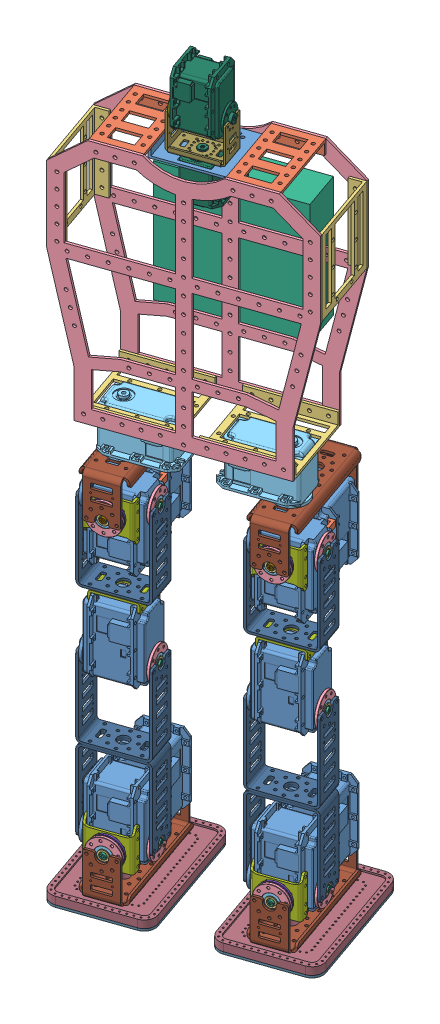
SolidWorks assembly main_new_feet_no_arm_update_motor, configuration Default. Lengths in mm.
Overall size (261.31 695.74 185.95).
113 component instances, 25 part files, 43 mates.
Components (placement in the parent):
- leg_l2-1: leg_l2 [Default] at (32.8984 -224.9307 -176.674) x (0.329122 0 0.944287) z (-0.944287 0 0.329122) size (106.88 70.06 58.88)
  - MX-106T_step-1: MX-106T_step [Default] at origin size (40.2 65.92 55.3)
  - MX-106T_step-2: MX-106T_step [Default] at (-44 0 0) x (0 0 1) z (-1 0 0) size (40.2 65.92 55.3)
  - FR08-X101_2017-1: FR08-X101_2017 [Default] at (-27 -7 -17) x (0 -1 0) z (0 0 1) size (28 12.3 4.8)
  - FR08-X101_2017-2: FR08-X101_2017 [Default] at (-27 -7 17) x (0 1 0) z (0 0 -1) size (28 12.3 4.8)
  - RX64-CAP_2017-1: RX64-CAP_2017 [Default] at (0 0 -25.78) x (0.56381 0.825904 0) z (0 0 -1) size (9.5 9.5 2.2)
  - HN05-I101_2017-1: HN05-I101_2017 [Default] at (0 0 -26.02) x (0.824833 -0.565376 0) z (0.565376 0.824833 0) size (28 3.77 28)
  - MF128ZZ_2017-1: MF128ZZ_2017 [Default] at (0 0 -22.3) x (-0.923728 -0.383049 0) z (0.383049 -0.923728 0) size (14 3.48 14)
  - WB_M2.5X8_2017-1: WB_M2.5X8_2017 [Default] at (0 0 -28.08) x (0 0 1) z (0.825904 -0.56381 0) size (5.5 4.5 4.5)
  - FR05-S101_2017-1: FR05-S101_2017 [Default] at (24 0 0) x (0 1 0) z (0 0 1) size (36 9.31 38.02)
  - FR05-F101_2017-1: FR05-F101_2017 [Default] at (24 0 0) x (0 -0.707107 0.707107) z (1 0 0) size (27 27 5)
  - MF128ZZ_2017-2: MF128ZZ_2017 [Default] at (26.3 0 0) x (0 -1 0) z (0 0 1) size (14 3.48 14)
  - WB_M2.5X8_step-1: WB_M2.5X8_step [Default] at (32.08 0 0) x (-1 0 0) z (0 0.546944 0.837169) size (10.5 4.5 4.5)
  - HN05-I101_2017-2: HN05-I101_2017 [Default] at (30.02 0 0) x (0 -1 0) z (0 0 1) size (28 3.77 28)
  - RX64-CAP_2017-2: RX64-CAP_2017 [Default] at (29.78 0 0) x (0 0.837169 -0.546944) z (1 0 0) size (9.5 9.5 2.2)
- leg_l3-2: leg_l3 [Default] at (28.5454 -310.8375 -119.8421) x (0.944287 0 -0.329122) z (0 1 0) size (58.88 41.6 149.21)
  - HW-64106HXL_2017-1: HW-64106HXL_2017 [Default] at (-3.1848 38.233 13.9067) size (56 28 75)
  - FR05-S101_2017-1: FR05-S101_2017 [Default] at (22.8152 52.233 13.9067) x (0 -1 0) z (1 0 0) size (36 9.31 38.02)
  - MX-106T_step-1: MX-106T_step [Default] at (22.8152 52.233 -40.5933) x (0 1 0) z (-1 0 0) size (40.2 65.92 55.3)
  - HN05-I101_2017-1: HN05-I101_2017 [Default] at (48.8352 52.233 -40.5933) x (0 -0.637924 -0.7701) z (0 -0.7701 0.637924) size (28 3.77 28)
  - RX64-CAP_2017-1: RX64-CAP_2017 [Default] at (48.5952 52.233 -40.5933) x (0 0.837169 -0.546944) z (1 0 0) size (9.5 9.5 2.2)
  - MF128ZZ_2017-1: MF128ZZ_2017 [Default] at (45.1152 52.233 -40.5933) x (0 -0.162836 -0.986653) z (0 -0.986653 0.162836) size (14 3.48 14)
  - WB_M2.5X8_2017-1: WB_M2.5X8_2017 [Default] at (50.8952 52.233 -40.5933) x (-1 0 0) z (0 0.546944 0.837169) size (5.5 4.5 4.5)
- leg_l4-1: leg_l4 [Default] at (8.2175 -492.0992 -119.3689) x (0.944287 0 -0.329122) z (0 1 0) size (56 28 150)
  - HW-64106HXL_2017-1: HW-64106HXL_2017 [Default] at (16.1663 31.9894 68.6685) size (56 28 75)
  - HW-64106HXL_2017-2: HW-64106HXL_2017 [Default] at (68.1663 31.9894 68.6685) x (-1 0 0) z (0 0 -1) size (56 28 75)
- leg_l5-1: leg_l5 [Default] at (63.8478 -442.1127 -223.3318) x (0.89528 -0.033567 0.444237) z (-0.424558 -0.366444 0.827931) size (104.02 99.97 119.36)
  - MX-106T_step-1: MX-106T_step [Default] at (-5.1915 -29.4269 71.3073) x (-0.714144 -0.278818 -0.642073) z (-0.699193 0.240141 0.673395) size (40.2 65.92 55.3)
  - MX-106T_step-2: MX-106T_step [Default] at (-36.6138 -41.6949 43.056) x (0.699193 -0.240141 -0.673395) z (-0.714144 -0.278818 -0.642073) size (40.2 65.92 55.3)
  - FR08-X101_2017-1: FR08-X101_2017 [Default] at (-36.5946 -26.3638 62.8539) x (-0.033567 0.929835 -0.366444) z (0.699193 -0.240141 -0.673395) size (28 12.3 4.8)
  - FR08-X101_2017-2: FR08-X101_2017 [Default] at (-12.8221 -34.5286 39.9585) x (0.033567 -0.929835 0.366444) z (-0.699193 0.240141 0.673395) size (28 12.3 4.8)
  - HN05-I101_2017-1: HN05-I101_2017 [Default] at (13.0015 -35.6754 53.7855) x (0.048348 -0.923861 0.379661) z (0.713296 0.298014 0.634347) size (28 3.77 28)
  - RX64-CAP_2017-1: RX64-CAP_2017 [Default] at (12.8337 -35.6178 53.9472) x (-0.430608 0.610431 -0.664793) z (0.699193 -0.240141 -0.673395) size (9.5 9.5 2.2)
  - HN05-I101_2017-2: HN05-I101_2017 [Default] at (16.2471 -21.0568 90.5823) x (0.601193 -0.714144 -0.35856) z (-0.35856 -0.642073 0.677626) size (28 3.77 28)
  - RX64-CAP_2017-2: RX64-CAP_2017 [Default] at (16.0757 -21.1237 90.4282) x (-0.307188 0.949038 -0.070448) z (0.714144 0.278818 0.642073) size (9.5 9.5 2.2)
  - MF128ZZ_2017-1: MF128ZZ_2017 [Default] at (10.4005 -34.7821 56.2906) x (0.048348 -0.923861 0.379661) z (0.713296 0.298014 0.634347) size (14 3.48 14)
  - WB_M2.5X8_2017-1: WB_M2.5X8_2017 [Default] at (14.4419 -36.1701 52.3983) x (-0.699193 0.240141 0.673395) z (0.570706 0.754788 0.323403) size (5.5 4.5 4.5)
  - MF128ZZ_2017-2: MF128ZZ_2017 [Default] at (13.5905 -22.094 88.1938) x (0.601193 -0.714144 -0.35856) z (-0.35856 -0.642073 0.677626) size (14 3.48 14)
  - WB_M2.5X8_2017-2: WB_M2.5X8_2017 [Default] at (17.7183 -20.4824 91.905) x (-0.714144 -0.278818 -0.642073) z (-0.628994 -0.146927 0.763399) size (5.5 4.5 4.5)
  - FR05-S101_2017-1: FR05-S101_2017 [Default] at (11.948 -22.7353 86.717) x (0.033567 -0.929835 0.366444) z (0.699193 -0.240141 -0.673395) size (36 9.31 38.02)
  - FR05-F101_2017-1: FR05-F101_2017 [Default] at (11.948 -22.7353 86.717) x (0.699193 -0.240141 -0.673395) z (0.714144 0.278818 0.642073) size (27 27 5)
- HW-64106HXW_2017-3: HW-64106HXW_2017 [Default] at (141.3019 -187.9307 -286.4689) x (0.329122 0 0.944287) z (0 -1 0) size (105 37.08 40)
- leg_l2-2: leg_l2 [Default] at (148.5736 -224.9307 -216.9914) x (0.329122 0 0.944287) z (-0.944287 0 0.329122) size (106.88 70.06 58.88)
  - MX-106T_step-1: MX-106T_step [Default] at origin size (40.2 65.92 55.3)
  - MX-106T_step-2: MX-106T_step [Default] at (-44 0 0) x (0 0 1) z (-1 0 0) size (40.2 65.92 55.3)
  - FR08-X101_2017-1: FR08-X101_2017 [Default] at (-27 -7 -17) x (0 -1 0) z (0 0 1) size (28 12.3 4.8)
  - FR08-X101_2017-2: FR08-X101_2017 [Default] at (-27 -7 17) x (0 1 0) z (0 0 -1) size (28 12.3 4.8)
  - RX64-CAP_2017-1: RX64-CAP_2017 [Default] at (0 0 -25.78) x (0.56381 0.825904 0) z (0 0 -1) size (9.5 9.5 2.2)
  - HN05-I101_2017-1: HN05-I101_2017 [Default] at (0 0 -26.02) x (0.824833 -0.565376 0) z (0.565376 0.824833 0) size (28 3.77 28)
  - MF128ZZ_2017-1: MF128ZZ_2017 [Default] at (0 0 -22.3) x (-0.923728 -0.383049 0) z (0.383049 -0.923728 0) size (14 3.48 14)
  - WB_M2.5X8_2017-1: WB_M2.5X8_2017 [Default] at (0 0 -28.08) x (0 0 1) z (0.825904 -0.56381 0) size (5.5 4.5 4.5)
  - FR05-S101_2017-1: FR05-S101_2017 [Default] at (24 0 0) x (0 1 0) z (0 0 1) size (36 9.31 38.02)
  - FR05-F101_2017-1: FR05-F101_2017 [Default] at (24 0 0) x (0 -0.707107 0.707107) z (1 0 0) size (27 27 5)
  - MF128ZZ_2017-2: MF128ZZ_2017 [Default] at (26.3 0 0) x (0 -1 0) z (0 0 1) size (14 3.48 14)
  - WB_M2.5X8_step-1: WB_M2.5X8_step [Default] at (32.08 0 0) x (-1 0 0) z (0 0.546944 0.837169) size (10.5 4.5 4.5)
  - HN05-I101_2017-2: HN05-I101_2017 [Default] at (30.02 0 0) x (0 -1 0) z (0 0 1) size (28 3.77 28)
  - RX64-CAP_2017-2: RX64-CAP_2017 [Default] at (29.78 0 0) x (0 0.837169 -0.546944) z (1 0 0) size (9.5 9.5 2.2)
- leg_l3-3: leg_l3 [Default] at (144.2206 -310.8375 -160.1595) x (0.944287 0 -0.329122) z (0 1 0) size (58.88 41.6 149.21)
  - HW-64106HXL_2017-1: HW-64106HXL_2017 [Default] at (-3.1848 38.233 13.9067) size (56 28 75)
  - FR05-S101_2017-1: FR05-S101_2017 [Default] at (22.8152 52.233 13.9067) x (0 -1 0) z (1 0 0) size (36 9.31 38.02)
  - MX-106T_step-1: MX-106T_step [Default] at (22.8152 52.233 -40.5933) x (0 1 0) z (-1 0 0) size (40.2 65.92 55.3)
  - HN05-I101_2017-1: HN05-I101_2017 [Default] at (48.8352 52.233 -40.5933) x (0 -0.637924 -0.7701) z (0 -0.7701 0.637924) size (28 3.77 28)
  - RX64-CAP_2017-1: RX64-CAP_2017 [Default] at (48.5952 52.233 -40.5933) x (0 0.837169 -0.546944) z (1 0 0) size (9.5 9.5 2.2)
  - MF128ZZ_2017-1: MF128ZZ_2017 [Default] at (45.1152 52.233 -40.5933) x (0 -0.162836 -0.986653) z (0 -0.986653 0.162836) size (14 3.48 14)
  - WB_M2.5X8_2017-1: WB_M2.5X8_2017 [Default] at (50.8952 52.233 -40.5933) x (-1 0 0) z (0 0.546944 0.837169) size (5.5 4.5 4.5)
- leg_l4-2: leg_l4 [Default] at (123.8927 -492.0992 -159.6864) x (0.944287 0 -0.329122) z (0 1 0) size (56 28 150)
  - HW-64106HXL_2017-1: HW-64106HXL_2017 [Default] at (16.1663 31.9894 68.6685) size (56 28 75)
  - HW-64106HXL_2017-2: HW-64106HXL_2017 [Default] at (68.1663 31.9894 68.6685) x (-1 0 0) z (0 0 -1) size (56 28 75)
- leg_l5-2: leg_l5 [Default] at (179.523 -442.1127 -263.6493) x (0.89528 -0.033567 0.444237) z (-0.424558 -0.366444 0.827931) size (104.02 99.97 119.36)
  - MX-106T_step-1: MX-106T_step [Default] at (-5.1915 -29.4269 71.3073) x (-0.714144 -0.278818 -0.642073) z (-0.699193 0.240141 0.673395) size (40.2 65.92 55.3)
  - MX-106T_step-2: MX-106T_step [Default] at (-36.6138 -41.6949 43.056) x (0.699193 -0.240141 -0.673395) z (-0.714144 -0.278818 -0.642073) size (40.2 65.92 55.3)
  - FR08-X101_2017-1: FR08-X101_2017 [Default] at (-36.5946 -26.3638 62.8539) x (-0.033567 0.929835 -0.366444) z (0.699193 -0.240141 -0.673395) size (28 12.3 4.8)
  - FR08-X101_2017-2: FR08-X101_2017 [Default] at (-12.8221 -34.5286 39.9585) x (0.033567 -0.929835 0.366444) z (-0.699193 0.240141 0.673395) size (28 12.3 4.8)
  - HN05-I101_2017-1: HN05-I101_2017 [Default] at (13.0015 -35.6754 53.7855) x (0.048348 -0.923861 0.379661) z (0.713296 0.298014 0.634347) size (28 3.77 28)
  - RX64-CAP_2017-1: RX64-CAP_2017 [Default] at (12.8337 -35.6178 53.9472) x (-0.430608 0.610431 -0.664793) z (0.699193 -0.240141 -0.673395) size (9.5 9.5 2.2)
  - HN05-I101_2017-2: HN05-I101_2017 [Default] at (16.2471 -21.0568 90.5823) x (0.601193 -0.714144 -0.35856) z (-0.35856 -0.642073 0.677626) size (28 3.77 28)
  - RX64-CAP_2017-2: RX64-CAP_2017 [Default] at (16.0757 -21.1237 90.4282) x (-0.307188 0.949038 -0.070448) z (0.714144 0.278818 0.642073) size (9.5 9.5 2.2)
  - MF128ZZ_2017-1: MF128ZZ_2017 [Default] at (10.4005 -34.7821 56.2906) x (0.048348 -0.923861 0.379661) z (0.713296 0.298014 0.634347) size (14 3.48 14)
  - WB_M2.5X8_2017-1: WB_M2.5X8_2017 [Default] at (14.4419 -36.1701 52.3983) x (-0.699193 0.240141 0.673395) z (0.570706 0.754788 0.323403) size (5.5 4.5 4.5)
  - MF128ZZ_2017-2: MF128ZZ_2017 [Default] at (13.5905 -22.094 88.1938) x (0.601193 -0.714144 -0.35856) z (-0.35856 -0.642073 0.677626) size (14 3.48 14)
  - WB_M2.5X8_2017-2: WB_M2.5X8_2017 [Default] at (17.7183 -20.4824 91.905) x (-0.714144 -0.278818 -0.642073) z (-0.628994 -0.146927 0.763399) size (5.5 4.5 4.5)
  - FR05-S101_2017-1: FR05-S101_2017 [Default] at (11.948 -22.7353 86.717) x (0.033567 -0.929835 0.366444) z (0.699193 -0.240141 -0.673395) size (36 9.31 38.02)
  - FR05-F101_2017-1: FR05-F101_2017 [Default] at (11.948 -22.7353 86.717) x (0.699193 -0.240141 -0.673395) z (0.714144 0.278818 0.642073) size (27 27 5)
- HW-64106HXW_2017-5: HW-64106HXW_2017 [Default] at (25.6267 -187.9307 -246.1515) x (0.329122 0 0.944287) z (0 -1 0) size (105 37.08 40)
- FR07-H101K-1: FR07-H101K [Default] at (93.0399 76.5333 -190.2227) x (-0.944287 0 0.329122) z (0 1 0) size (44 26 32.5)
- leg_l6_new_feet-1: leg_l6_new_feet [Default] at (87.7926 -593.8701 -169.2992) x (-0.329122 0 -0.944287) z (0 1 0) size (120 80 47.5)
  - HW-64106HXW_2017-1: HW-64106HXW_2017 [Default] at (-3.9692 33.4087 61.4394) size (105 37.08 40)
  - foot_new-1: foot_new [Default] at (44.5308 49.4087 55.9394) x (1 0 0) z (0 -1 0) size (120 7 80)
  - Part4^leg_l6_new_feet-1: Part4^leg_l6_new_feet [Default] at (44.5308 49.4087 55.9394) x (-1 0 0) z (0 0 -1) size (120 80 2) (virtual)
- leg_l6_new_feet-2: leg_l6_new_feet [Default] at (203.4678 -593.8701 -209.6167) x (-0.329122 0 -0.944287) z (0 1 0) size (120 80 47.5)
  - HW-64106HXW_2017-1: HW-64106HXW_2017 [Default] at (-3.9692 33.4087 61.4394) size (105 37.08 40)
  - foot_new-1: foot_new [Default] at (44.5308 49.4087 55.9394) x (1 0 0) z (0 -1 0) size (120 7 80)
  - Part4^leg_l6_new_feet-1: Part4^leg_l6_new_feet [Default] at (44.5308 49.4087 55.9394) x (-1 0 0) z (0 0 -1) size (120 80 2) (virtual)
- head_2_no_camera-1: head_2_no_camera [Default] at (57.4956 210.3096 -243.8587) x (0.944287 0 -0.329122) z (0.329122 0 0.944287) size (44.45 51.16 35.6)
  - MX28_step-1: MX28_step [Default] at (-26.9298 -63.9825 50.4384) x (0 0 1) z (1 0 0) size (35.6 50.71 42.6)
  - MX28_HN07-i101-1: MX28_HN07-i101 [Default] at (-4.5387 -101.2764 62.3462) x (0 0.153917 -0.988084) z (0 0.988084 0.153917) size (22 3.05 22)
  - MF106ZZ-1: MF106ZZ [Défaut] at (-4.3887 -101.2764 62.3462) x (0 0.577041 0.816715) z (0 0.816715 -0.577041) size (11.2 3 11.2)
  - RX28-CAP-1: RX28-CAP [Défaut] at (-4.3887 -101.2764 62.3462) x (0 1 0) z (-1 0 0) size (7.2 7.2 1.8)
- torso_no_arm_motor-1: torso_no_arm_motor [Default] at (90.5715 74.6103 -197.3049) x (0.944287 0 -0.329122) z (0.329122 0 0.944287) size (200 273.5 112.95)
  - torso_frame_head-1: torso_frame_head [Default] at (0 -3.827 -35) size (76 8 58.5)
  - torso_frame_link-1: torso_frame_link [Default] at (-50 -6.241 0) x (0 0 1) z (-1 0 0) size (75.11 12.7 53.47)
  - torso_frame_motor-1: torso_frame_motor [Default] at (-98.857 -88.541 0) x (0 0 1) z (-1 0 0) size (68 70 36.25)
  - torso_main-1: torso_main [Default] at (0 0 34) size (200 228.5 2.29)
  - torso_main-2: torso_main [Default] at (0 0 -36.286) size (200 228.5 2.29)
  - torso_frame_link-2: torso_frame_link [Default] at (50 -6.241 0) x (0 0 1) z (-1 0 0) size (75.11 12.7 53.47)
  - torso_frame_motor-2: torso_frame_motor [Default] at (98.857 -88.541 0) x (0 0 -1) z (1 0 0) size (68 70 36.25)
  - torso_frame_motor-3: torso_frame_motor [Default] at (10 -220.898 0) x (0 0 -1) z (0 -1 0) size (68 70 36.25)
  - torso_frame_motor-4: torso_frame_motor [Default] at (-10 -220.898 0) x (0 0 1) z (0 -1 0) size (68 70 36.25)
  - MX-64T_step-3: MX-64T_step [Default] at (61.25 -239.041 0) x (0 0 -1) z (0 -1 0) size (40.2 62.1 50)
  - MX-64T_step-4: MX-64T_step [Default] at (-61.25 -239.041 0) x (0 0 1) z (0 -1 0) size (40.2 62.1 50)
  - MX28_step-1: MX28_step [Default] at (11.9078 -61.4181 -29.7938) x (-1 0 0) z (0 1 0) size (35.6 50.71 42.6)
  - nuc-1: nuc [Default] at (0 -108.0269 -54.066) size (114.3 111.76 35.56)
- Part1^main_new_feet_no_arm_update_motor-1: Part1^main_new_feet_no_arm_update_motor [Default] at origin (virtual)
Mates (geometry in assembly coordinates):
- Concentric3: concentric anti-aligned: cylinder of leg_l2-1/HN05-I101_2017-1 through (57.4688 -224.9307 -185.2377) axis (-0.944287 0 0.329122) radius 14; cylinder of leg_l3-2/HW-64106HXL_2017-1 through (59.3385 -224.9307 -185.8894) axis (0.944287 0 -0.329122) radius 5.1
- Concentric4: concentric anti-aligned: cylinder of leg_l3-2/HN05-I101_2017-1 through (57.4688 -351.4307 -185.2377) axis (-0.944287 0 0.329122) radius 14; cylinder of leg_l4-1/HW-64106HXL_2017-1 through (59.3385 -351.4307 -185.8894) axis (0.944287 0 -0.329122) radius 5.1
- Concentric5: concentric anti-aligned: cylinder of leg_l4-1/HW-64106HXL_2017-2 through (6.4584 -495.4307 -167.4586) axis (-0.944287 0 0.329122) radius 5.1; cylinder of leg_l5-1/MX-106T_step-1 through (3.4461 -495.4307 -166.4087) axis (0.944287 0 -0.329122) radius 5
- Coincident5: coincident anti-aligned: plane of leg_l4-1/HW-64106HXL_2017-2 through (8.347 -495.4307 -168.1168) normal (0.944287 0 -0.329122); plane of leg_l5-1/MX-106T_step-1 through (8.347 -495.4307 -168.1168) normal (-0.944287 0 0.329122)
- Coincident6: coincident anti-aligned: plane of leg_l2-1/MX-106T_step-1 through (8.347 -224.9307 -168.1168) normal (-0.944287 0 0.329122); plane of leg_l3-2/HW-64106HXL_2017-1 through (8.347 -224.9307 -168.1168) normal (0.944287 0 -0.329122)
- Coincident7: coincident anti-aligned: plane of leg_l2-1/MX-106T_step-1 through (8.347 -224.9307 -168.1168) normal (-0.944287 0 0.329122); plane of leg_l3-2/HW-64106HXL_2017-1 through (8.347 -224.9307 -168.1168) normal (0.944287 0 -0.329122)
- Coincident8: coincident anti-aligned: plane of leg_l3-2/MX-106T_step-1 through (8.347 -351.4307 -168.1168) normal (-0.944287 0 0.329122); plane of leg_l4-1/HW-64106HXL_2017-1 through (8.347 -351.4307 -168.1168) normal (0.944287 0 -0.329122)
- Concentric8: concentric aligned: cylinder of HW-64106HXW_2017-3 through (159.4347 -224.9307 -185.83) axis (0.329122 0 0.944287) radius 5.1; cylinder of leg_l2-2/MX-106T_step-2 through (123.8269 -224.9307 -287.9924) axis (0.329122 0 0.944287) radius 5
- Coincident11: coincident anti-aligned: plane of HW-64106HXW_2017-3 through (125.5351 -210.0147 -283.0916) normal (0.329122 0 0.944287); plane of leg_l2-2/MX-106T_step-2 through (125.5351 -224.9307 -283.0916) normal (-0.329122 0 -0.944287)
- Concentric9: concentric aligned: cylinder of leg_l2-2/MX-106T_step-1 through (119.1213 -224.9307 -206.7261) axis (0.944287 0 -0.329122) radius 5; cylinder of leg_l3-3/HW-64106HXL_2017-1 through (124.0222 -224.9307 -208.4343) axis (0.944287 0 -0.329122) radius 5.1
- Coincident12: coincident anti-aligned: plane of leg_l2-2/MX-106T_step-1 through (124.0222 -224.9307 -208.4343) normal (-0.944287 0 0.329122); plane of leg_l3-3/HW-64106HXL_2017-1 through (124.0222 -224.9307 -208.4343) normal (0.944287 0 -0.329122)
- Concentric10: concentric aligned: cylinder of leg_l3-3/MX-106T_step-1 through (119.1213 -351.4307 -206.7261) axis (0.944287 0 -0.329122) radius 5; cylinder of leg_l4-2/HW-64106HXL_2017-1 through (124.0222 -351.4307 -208.4343) axis (0.944287 0 -0.329122) radius 5.1
- Coincident13: coincident anti-aligned: plane of leg_l3-3/MX-106T_step-1 through (124.0222 -351.4307 -208.4343) normal (-0.944287 0 0.329122); plane of leg_l4-2/HW-64106HXL_2017-1 through (124.0222 -351.4307 -208.4343) normal (0.944287 0 -0.329122)
- Concentric13: concentric anti-aligned: cylinder of leg_l4-2/HW-64106HXL_2017-2 through (122.1336 -495.4307 -207.776) axis (-0.944287 0 0.329122) radius 5.1; cylinder of leg_l5-2/MX-106T_step-1 through (119.1213 -495.4307 -206.7261) axis (0.944287 0 -0.329122) radius 5
- Coincident16: coincident anti-aligned: plane of leg_l4-2/HW-64106HXL_2017-2 through (124.0222 -495.4307 -208.4343) normal (0.944287 0 -0.329122); plane of leg_l5-2/MX-106T_step-1 through (124.0222 -495.4307 -208.4343) normal (-0.944287 0 0.329122)
- Parallel3: parallel anti-aligned: plane of leg_l2-1/MX-106T_step-1 through (32.8984 -224.9307 -176.674) normal (0.329122 0 0.944287); plane of leg_l3-2/HW-64106HXL_2017-1 through (12.9547 -296.9307 -154.8968) normal (-0.329122 0 -0.944287)
- Parallel4: parallel aligned: plane of leg_l3-2/MX-106T_step-1 through (32.8984 -351.4307 -176.674) normal (-0.329122 0 -0.944287); plane of leg_l4-1/HW-64106HXL_2017-1 through (12.9547 -423.4307 -154.8968) normal (-0.329122 0 -0.944287)
- Parallel5: parallel aligned: plane of leg_l4-1/HW-64106HXL_2017-2 through (62.0576 -423.4307 -172.0111) normal (-0.329122 0 -0.944287); plane of leg_l5-1/MX-106T_step-1 through (32.8984 -495.4307 -176.674) normal (-0.329122 0 -0.944287)
- Parallel8: parallel aligned: plane of HW-64106HXW_2017-3 through (141.3019 -187.9307 -286.4689) normal (-0.944287 0 0.329122); plane of leg_l2-2/MX-106T_step-1 through (148.5736 -224.9307 -216.9914) normal (-0.944287 0 0.329122)
- Parallel9: parallel anti-aligned: plane of leg_l2-2/MX-106T_step-1 through (148.5736 -224.9307 -216.9914) normal (0.329122 0 0.944287); plane of leg_l3-3/HW-64106HXL_2017-1 through (128.6299 -296.9307 -195.2142) normal (-0.329122 0 -0.944287)
- Parallel10: parallel aligned: plane of leg_l3-3/MX-106T_step-1 through (148.5736 -351.4307 -216.9914) normal (-0.329122 0 -0.944287); plane of leg_l4-2/HW-64106HXL_2017-1 through (128.6299 -423.4307 -195.2142) normal (-0.329122 0 -0.944287)
- Parallel11: parallel aligned: plane of leg_l4-2/HW-64106HXL_2017-2 through (177.7328 -423.4307 -212.3286) normal (-0.329122 0 -0.944287); plane of leg_l5-2/MX-106T_step-1 through (148.5736 -495.4307 -216.9914) normal (-0.329122 0 -0.944287)
- Concentric19: concentric aligned: cylinder of leg_l2-1/MX-106T_step-2 through (8.1517 -224.9307 -247.6749) axis (0.329122 0 0.944287) radius 5; cylinder of HW-64106HXW_2017-5 through (43.7595 -224.9307 -145.5125) axis (0.329122 0 0.944287) radius 5.1
- Coincident39: coincident anti-aligned: plane of leg_l2-1/MX-106T_step-2 through (9.8599 -224.9307 -242.7741) normal (-0.329122 0 -0.944287); plane of HW-64106HXW_2017-5 through (9.8599 -210.0147 -242.7741) normal (0.329122 0 0.944287)
- Parallel18: parallel aligned: plane of leg_l2-1/MX-106T_step-1 through (32.8984 -224.9307 -176.674) normal (-0.944287 0 0.329122); plane of HW-64106HXW_2017-5 through (25.6267 -187.9307 -246.1515) normal (-0.944287 0 0.329122)
- Concentric34: concentric anti-aligned: cylinder of FR07-H101K-1 through (72.2656 109.0333 -182.982) axis (0.944287 0 -0.329122) radius 4; cylinder of head_2_no_camera-1/MX28_step-1 through (115.3652 109.0333 -198.004) axis (-0.944287 0 0.329122) radius 11
- Concentric35: concentric aligned: cylinder of FR07-H101K-1 through (93.0399 78.0333 -190.2227) axis (0 -1 0) radius 4; cylinder of torso_no_arm_motor-1/MX28_step-1 through (93.0399 79.6758 -190.2227) axis (0 -1 0) radius 4
- Coincident59: coincident anti-aligned: plane of FR07-H101K-1 through (93.0399 76.5333 -190.2227) normal (0 -1 0); plane of torso_no_arm_motor-1/MX28_step-1 through (93.0399 76.5333 -190.2227) normal (0 1 0)
- Concentric36: concentric anti-aligned: cylinder of HW-64106HXW_2017-5 through (32.7339 -306.252 -177.1461) axis (0 -1 0) radius 5.1; cylinder of torso_no_arm_motor-1/MX-64T_step-4 through (32.7339 -192.8057 -177.1461) axis (0 1 0) radius 14
- Coincident61: coincident anti-aligned: plane of HW-64106HXW_2017-5 through (34.7909 -187.9307 -171.2443) normal (0 1 0); plane of torso_no_arm_motor-1/MX-64T_step-4 through (32.7339 -187.9307 -177.1461) normal (0 -1 0)
- Parallel32: parallel aligned: plane of HW-64106HXW_2017-5 through (8.9735 -191.5147 -188.9857) normal (-0.944287 0 0.329122); plane of torso_no_arm_motor-1/MX-64T_step-4 through (25.2304 -143.9307 -159.1754) normal (-0.944287 0 0.329122)
- Concentric37: concentric anti-aligned: cylinder of HW-64106HXW_2017-3 through (148.4091 -306.252 -217.4636) axis (0 -1 0) radius 5.1; cylinder of torso_no_arm_motor-1/MX-64T_step-3 through (148.4091 -192.8057 -217.4636) axis (0 1 0) radius 14
- Coincident63: coincident anti-aligned: plane of HW-64106HXW_2017-3 through (150.4661 -187.9307 -211.5618) normal (0 1 0); plane of torso_no_arm_motor-1/MX-64T_step-3 through (148.4091 -187.9307 -217.4636) normal (0 -1 0)
- Parallel33: parallel aligned: plane of HW-64106HXW_2017-3 through (159.6628 -191.5147 -241.507) normal (0.944287 0 -0.329122); plane of torso_no_arm_motor-1/MX-64T_step-3 through (155.9125 -143.9307 -235.4343) normal (0.944287 0 -0.329122)
- Concentric38: concentric anti-aligned: cylinder of leg_l5-1/HN05-I101_2017-2 through (42.7787 -495.4307 -148.3265) axis (-0.329122 0 -0.944287) radius 14; circle of leg_l6_new_feet-1/HW-64106HXW_2017-1
- Parallel34: parallel aligned: plane of leg_l5-1/MX-106T_step-1 through (49.8448 -509.9307 -197.936) normal (0 -1 0); plane of leg_l6_new_feet-1/foot_new-1 through (26.4806 -537.9307 -195.0876) normal (0 -1 0)
- Concentric39: concentric aligned: cylinder of leg_l5-2/HN05-I101_2017-2 through (158.4539 -495.4307 -188.6439) axis (-0.329122 0 -0.944287) radius 14; cylinder of leg_l6_new_feet-2/HW-64106HXW_2017-1 through (124.8768 -495.4307 -284.9801) axis (-0.329122 0 -0.944287) radius 5.1
- Parallel35: parallel aligned: plane of leg_l5-2/MX-106T_step-1 through (165.52 -509.9307 -238.2534) normal (0 -1 0); plane of leg_l6_new_feet-2/foot_new-1 through (142.1558 -537.9307 -235.405) normal (0 -1 0)
- Coincident70: coincident anti-aligned: plane of leg_l5-1/MX-106T_step-2 through (9.8599 -495.4307 -242.7741) normal (-0.329122 0 -0.944287); plane of leg_l6_new_feet-1/HW-64106HXW_2017-1 through (9.8599 -510.3468 -242.7741) normal (0.329122 0 0.944287)
- Coincident71: coincident anti-aligned: plane of leg_l5-2/MX-106T_step-2 through (125.5351 -495.4307 -283.0916) normal (-0.329122 0 -0.944287); plane of leg_l6_new_feet-2/HW-64106HXW_2017-1 through (125.5351 -510.3468 -283.0916) normal (0.329122 0 0.944287)
- Coincident72: coincident anti-aligned: plane of FR07-H101K-1 through (112.3978 109.0333 -196.9697) normal (-0.944287 0 0.329122); plane of head_2_no_camera-1/MX28_step-1 through (112.3978 109.0333 -196.9697) normal (0.944287 0 -0.329122)
- Parallel36: parallel aligned: plane of head_2_no_camera-1/MX28_step-1 through (86.3865 141.6333 -169.0535) normal (0.329122 0 0.944287); plane of FR07-H101K-1 through (77.3023 76.5333 -173.0885) normal (0.329122 0 0.944287)
- Parallel37: parallel aligned: plane of FR07-H101K-1 through (77.3023 76.5333 -173.0885) normal (0.329122 0 0.944287); plane of torso_no_arm_motor-1/torso_main-1 through (102.514 114.6103 -163.0404) normal (0.329122 0 0.944287)
